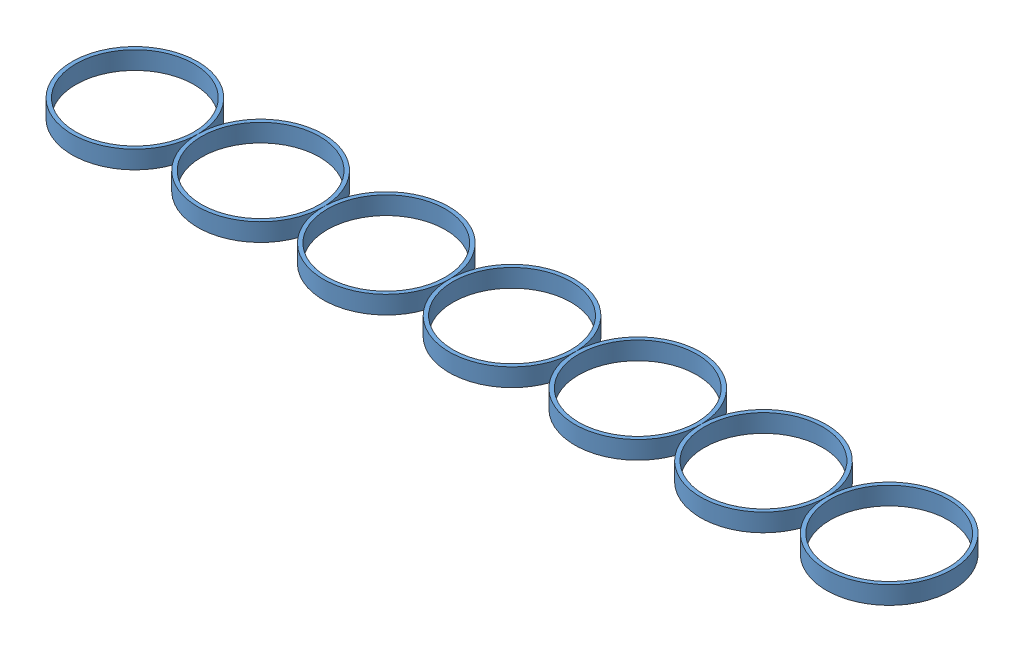
SolidWorks assembly lapghepmoi, configuration Default. Lengths in mm.
Overall size (343 7 49).
7 component instances, 1 part files, 18 mates.
Components (placement in the parent):
- 1oluoi-1: 1oluoi [Default] at (-2.097 23.8571 47.1563) size (49 7 49)
- 1oluoi-2: 1oluoi [Default] at (46.903 23.8571 47.1563) size (49 7 49)
- 1oluoi-3: 1oluoi [Default] at (-51.097 23.8571 47.1563) size (49 7 49)
- 1oluoi-4: 1oluoi [Default] at (-100.097 23.8571 47.1563) size (49 7 49)
- 1oluoi-5: 1oluoi [Default] at (95.903 23.8571 47.1563) size (49 7 49)
- 1oluoi-6: 1oluoi [Default] at (-149.097 23.8571 47.1563) size (49 7 49)
- 1oluoi-7: 1oluoi [Default] at (-198.097 23.8571 47.1563) size (49 7 49)
Mates (geometry in assembly coordinates):
- Tangent1: tangent anti-aligned: cylinder of 1oluoi-1 through (-2.097 30.8571 47.1563) axis (0 -1 0) radius 24.5; cylinder of 1oluoi-2 through (46.903 30.8571 47.1563) axis (0 -1 0) radius 24.5
- Coincident1: coincident aligned: plane of 1oluoi-1 through (-2.097 30.8571 47.1563) normal (0 1 0); plane of 1oluoi-2 through (46.903 30.8571 47.1563) normal (0 1 0)
- Tangent2: tangent anti-aligned: cylinder of 1oluoi-2 through (46.903 30.8571 47.1563) axis (0 -1 0) radius 24.5; plane of assembly
- Tangent3: tangent anti-aligned: cylinder of 1oluoi-3 through (-51.097 30.8571 47.1563) axis (0 -1 0) radius 24.5; plane of assembly
- Coincident2: coincident aligned: plane of 1oluoi-1 through (-2.097 30.8571 47.1563) normal (0 1 0); plane of 1oluoi-3 through (-51.097 30.8571 47.1563) normal (0 1 0)
- Tangent4: tangent anti-aligned: cylinder of 1oluoi-1 through (-2.097 30.8571 47.1563) axis (0 -1 0) radius 24.5; cylinder of 1oluoi-3 through (-51.097 30.8571 47.1563) axis (0 -1 0) radius 24.5
- Tangent5: tangent anti-aligned: cylinder of 1oluoi-2 through (46.903 30.8571 47.1563) axis (0 -1 0) radius 24.5; cylinder of 1oluoi-5 through (95.903 30.8571 47.1563) axis (0 -1 0) radius 24.5
- Tangent6: tangent anti-aligned: cylinder of 1oluoi-5 through (95.903 30.8571 47.1563) axis (0 -1 0) radius 24.5; plane of assembly
- Coincident3: coincident aligned: plane of 1oluoi-2 through (46.903 30.8571 47.1563) normal (0 1 0); plane of 1oluoi-5 through (95.903 30.8571 47.1563) normal (0 1 0)
- Tangent7: tangent anti-aligned: cylinder of 1oluoi-3 through (-51.097 30.8571 47.1563) axis (0 -1 0) radius 24.5; cylinder of 1oluoi-4 through (-100.097 30.8571 47.1563) axis (0 -1 0) radius 24.5
- Tangent8: tangent anti-aligned: cylinder of 1oluoi-4 through (-100.097 30.8571 47.1563) axis (0 -1 0) radius 24.5; plane of assembly
- Coincident4: coincident aligned: plane of 1oluoi-3 through (-51.097 30.8571 47.1563) normal (0 1 0); plane of 1oluoi-4 through (-100.097 30.8571 47.1563) normal (0 1 0)
- Tangent11: tangent anti-aligned: cylinder of 1oluoi-4 through (-100.097 30.8571 47.1563) axis (0 -1 0) radius 24.5; cylinder of 1oluoi-6 through (-149.097 30.8571 47.1563) axis (0 -1 0) radius 24.5
- Coincident6: coincident aligned: plane of 1oluoi-4 through (-100.097 30.8571 47.1563) normal (0 1 0); plane of 1oluoi-6 through (-149.097 30.8571 47.1563) normal (0 1 0)
- Tangent12: tangent anti-aligned: cylinder of 1oluoi-6 through (-149.097 30.8571 47.1563) axis (0 -1 0) radius 24.5; plane of assembly
- Tangent13: tangent anti-aligned: cylinder of 1oluoi-6 through (-149.097 30.8571 47.1563) axis (0 -1 0) radius 24.5; cylinder of 1oluoi-7 through (-198.097 30.8571 47.1563) axis (0 -1 0) radius 24.5
- Coincident7: coincident aligned: plane of 1oluoi-6 through (-149.097 30.8571 47.1563) normal (0 1 0); plane of 1oluoi-7 through (-198.097 30.8571 47.1563) normal (0 1 0)
- Tangent14: tangent anti-aligned: cylinder of 1oluoi-7 through (-198.097 30.8571 47.1563) axis (0 -1 0) radius 24.5; plane of assembly
